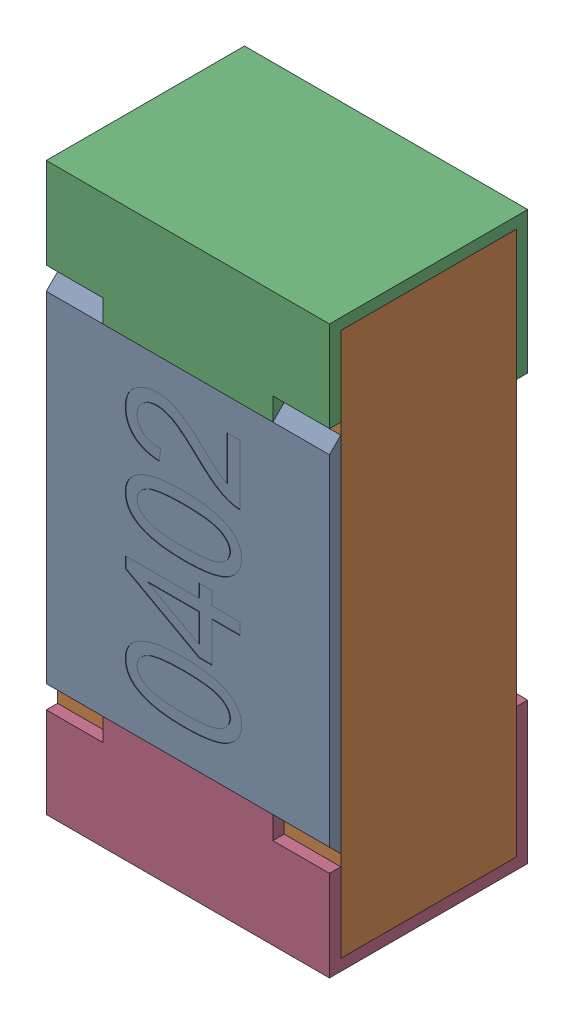
SolidWorks assembly R16, configuration Standard. Lengths in mm.
Overall size (0.5 1 0.35).
5 component instances, 4 part files, 0 mates.
Components (placement in the parent):
- R16-subassembly-1-1: R16-subassembly-1 [Standard] at (-9.1 -14.2999 0) x (0 1 0) z (0 0 1) size (1 0.5 0.35)
  - User Library-R_0402-1: User Library-R_0402 [Standard] at origin size (0.64 0.5 0.02)
  - User Library-R_0402-1-1: User Library-R_0402-1 [Standard] at origin size (0.96 0.5 0.31)
  - User Library-R_0402-2-1: User Library-R_0402-2 [Standard] at origin size (0.25 0.5 0.35)
  - User Library-R_0402-3-1: User Library-R_0402-3 [Standard] at origin size (0.25 0.5 0.35)
